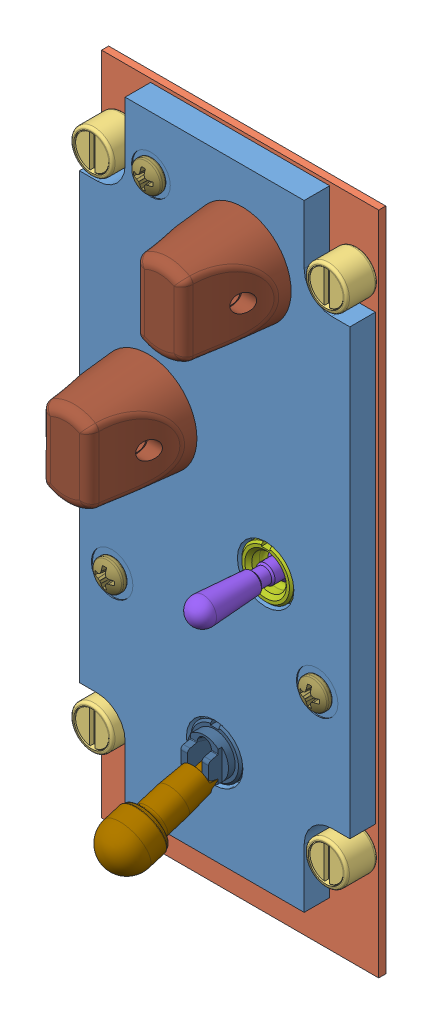
SolidWorks assembly EXT LT Panel Ref, configuration Default. Lengths in mm.
Overall size (63.5 152.4 40.02).
25 component instances, 12 part files, 2 mates.
Components (placement in the parent):
- EXT LT Light Plate Ref-1: EXT LT Light Plate Ref [Default] at origin size (61.98 141.29 5.84)
- EXT LT Mount Plate Ref-1: EXT LT Mount Plate Ref [Default] at origin size (63.5 152.4 1.63)
- D5 DZUS Stud Ref v1-1: D5 DZUS Stud Ref v1 [Default] at (4.8895 23.8125 1.6256) size (9.65 9.65 8.83)
- D5 DZUS Stud Ref v1-2: D5 DZUS Stud Ref v1 [Default] at (4.8895 138.1125 1.6256) size (9.65 9.65 8.83)
- D5 DZUS Stud Ref v1-3: D5 DZUS Stud Ref v1 [Default] at (58.6105 23.8125 1.6256) size (9.65 9.65 8.83)
- D5 DZUS Stud Ref v1-4: D5 DZUS Stud Ref v1 [Default] at (58.6105 138.1125 1.6256) size (9.65 9.65 8.83)
- MS25081-4 v1-1: MS25081-4 v1 [Default] at (31.75 31.75 -1.016) size (18.26 19.09 2.29)
- MS25082-8 v2-1: MS25082-8 v2 [Default] at (31.75 31.75 -2.0066) size (15.08 16.48 1.98)
- MS35333-126 v1-1: MS35333-126 v1 [Default] at (31.75 31.75 1.8542) size (15.24 15.24 0.71)
- MS25082-8 v2-2: MS25082-8 v2 [Default] at (31.75 31.75 3.0734) size (15.08 16.48 1.98)
- MS25081-4 v1-2: MS25081-4 v1 [Default] at (43.434 73.025 -1.016) size (18.26 19.09 2.29)
- MS25082-8 v2-3: MS25082-8 v2 [Default] at (43.434 73.025 -2.0066) size (15.08 16.48 1.98)
- MS35333-126 v1-2: MS35333-126 v1 [Default] at (43.434 73.025 1.8542) size (15.24 15.24 0.71)
- MS25082-8 v2-4: MS25082-8 v2 [Default] at (43.434 73.025 3.0734) size (15.08 16.48 1.98)
- MS Toggle Switch Sealed 3-Position Ref v1-1: MS Toggle Switch Sealed 3-Position Ref v1 [Default] at (2.159 60.325 1.7107) size (14.29 14.29 30.73)
  - Toggle Threads Sealed Ref-1: Toggle Threads Sealed Ref [Default] at (41.275 12.7 -6.1811) x (-1 0 0) z (0 0 1) size (14.29 14.29 13.21)
  - Toggle Lever Sealed Ref-1: Toggle Lever Sealed Ref [Default] at (41.275 12.7 -6.1811) x (-1 0 0) z (0 0 1) size (10.67 7.94 27.59)
- MS Toggle Switch Locking D Ref v4-1: MS Toggle Switch Locking D Ref v4 [Default] at origin size (14.29 21.75 40.02)
  - Toggle Lever Locking Round Ref-1: Toggle Lever Locking Round Ref [Default] at (31.75 33.5323 -4.204) x (-1 0 0) z (0 -0.292372 0.956305) size (10.67 10.67 36.48)
  - Toggle Threads Locking Ref-1: Toggle Threads Locking Ref [Default] at (31.75 31.75 -4.4704) x (-1 0 0) z (0 0 1) size (14.29 14.29 17.78)
- MS21385-04CNN v1-1: MS21385-04CNN v1 [Default] at (16.51 92.075 7.4676) x (-1 0 0) z (0 0 1) size (22.35 22.35 19.07)
- MS21385-04CNN v1-2: MS21385-04CNN v1 [Default] at (38.1 132.08 7.4676) x (-1 0 0) z (0 0 1) size (22.35 22.35 19.07)
- No. 6 Pan Head Phillips Machine Screw Ref v2-1: No. 6 Pan Head Phillips Machine Screw Ref v2 [Default] at (8.255 55.5625 4.0386) size (6.9 6.86 4.05)
- No. 6 Pan Head Phillips Machine Screw Ref v2-2: No. 6 Pan Head Phillips Machine Screw Ref v2 [Default] at (55.245 55.5625 4.0386) size (6.9 6.86 4.05)
- No. 6 Pan Head Phillips Machine Screw Ref v2-3: No. 6 Pan Head Phillips Machine Screw Ref v2 [Default] at (17.145 139.192 4.0386) size (6.9 6.86 4.05)
Mates (geometry in assembly coordinates):
- Concentric1: concentric aligned: cylinder of EXT LT Light Plate Ref-1 through (43.434 73.025 7.4676) axis (0 0 -1) radius 6.477; cylinder of MS Toggle Switch Sealed 3-Position Ref v1-1/Toggle Threads Sealed Ref-1 through (43.434 73.025 1.4986) axis (0 0 -1) radius 5.922
- Coincident2: coincident aligned: plane of MS Toggle Switch Sealed 3-Position Ref v1-1/Toggle Threads Sealed Ref-1 through (43.434 67.0719 7.4676) normal (0 0 1); plane of MS Toggle Switch Locking D Ref v4-1/Toggle Threads Locking Ref-1 through (31.75 25.7969 7.4676) normal (0 0 1)
